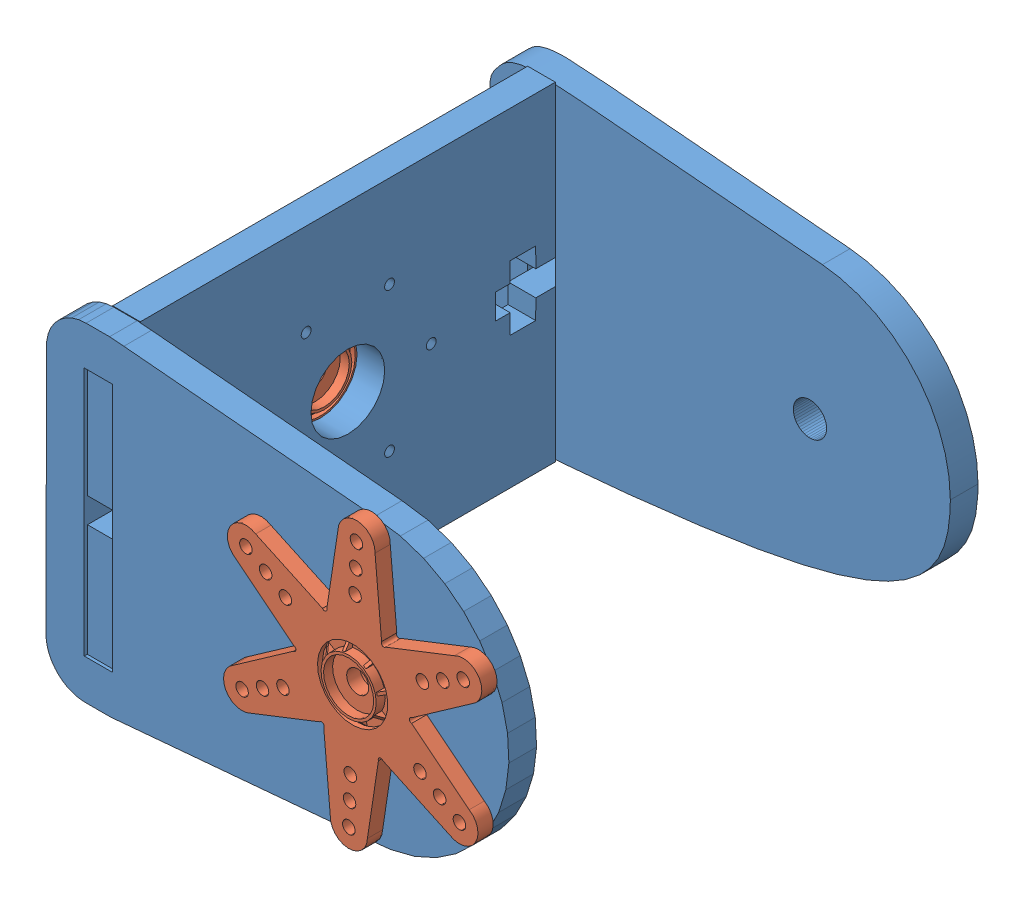
SolidWorks assembly left_shoulder, configuration Default. Lengths in mm.
Overall size (65.53 49.16 61.98).
3 component instances, 2 part files, 2 mates.
Components (placement in the parent):
- left_shoulder_100-2: left_shoulder_100 [Default] at (11.225 30.5666 56.6447) size (63.18 46.66 59.55)
- servo_arm_6_sided-1: servo_arm_6_sided [Default] at (52.1085 59.6873 116.1877) x (-0.850356 0.526207 0) z (0.526207 0.850356 0) size (36.45 6.25 32.2)
- servo_arm_6_sided-4: servo_arm_6_sided [Default] at (14.3535 59.7365 86.4004) x (0 -0.868323 -0.495999) z (0 -0.495999 0.868323) size (36.45 6.25 32.2)
Mates (geometry in assembly coordinates):
- Concentric1: concentric aligned: circle of left_shoulder_100-2; circle of servo_arm_6_sided-1
- Concentric3: concentric anti-aligned: circle of left_shoulder_100-2; circle of servo_arm_6_sided-4
